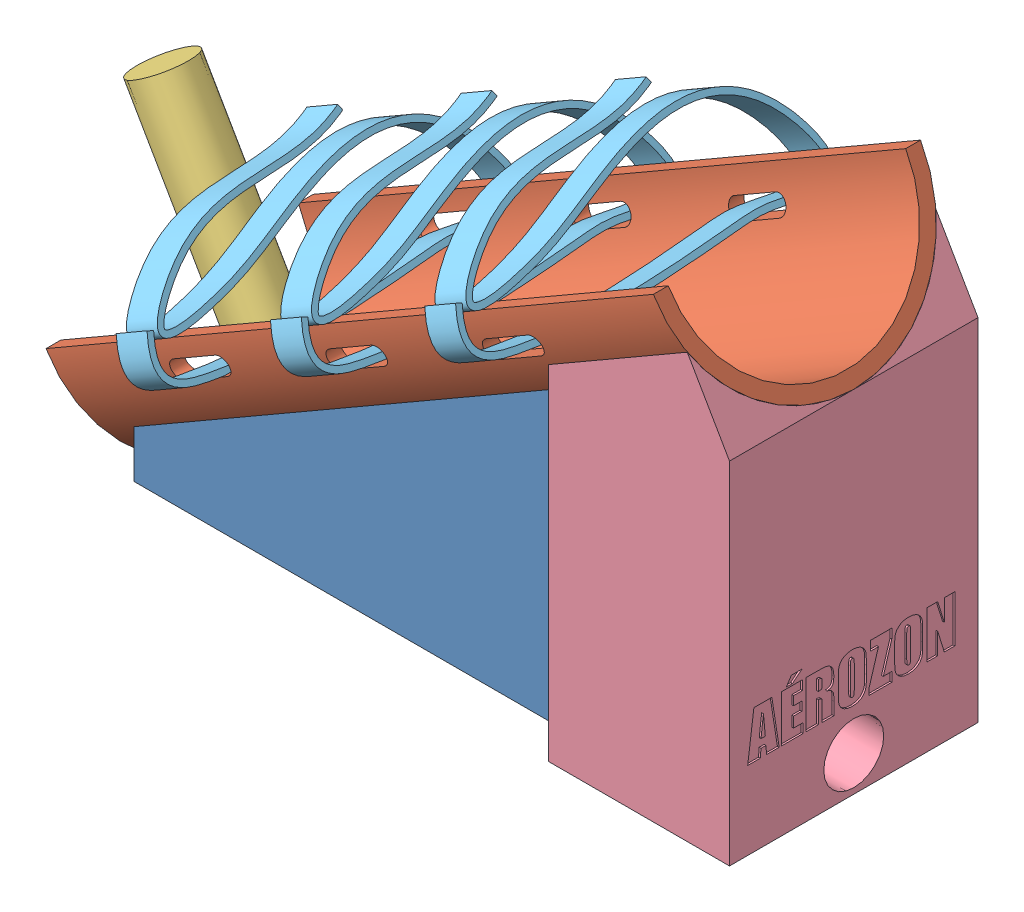
SolidWorks assembly Assem3, configuration Default. Lengths in mm.
Overall size (306.64 199.5 154.54).
5 component instances, 5 part files, 4 mates.
Components (placement in the parent):
- Foam Block-2: Foam Block [Default] at (0 71.68 48.07) x (1 0 0) z (0 1 0) size (228 96.14 140.29)
- Part2^Assem3-1: Part2^Assem3 [Default] at origin size (288.38 199.49 114.3) (virtual)
- Part3^Assem3-1: Part3^Assem3 [Default] at origin size (272.45 126.84 25.4) (virtual)
- Part5^Assem3-1: Part5^Assem3 [Default] at origin size (77.37 181.3 106.3)
- Part6^Assem3-1: Part6^Assem3 [Default] at origin size (174.47 134.55 154.54) (virtual)
Mates (geometry in assembly coordinates):
- Parallel1: parallel anti-aligned: plane of Foam Block-2 through (0 71.68 -48.07) normal (0 0 -1)
- Coincident1: coincident: point of Foam Block-2
- Coincident2: coincident anti-aligned: plane of Foam Block-2 through (-114 0 -48.07) normal (0 -1 0)
- Coincident3: coincident: unknown of Foam Block-2
